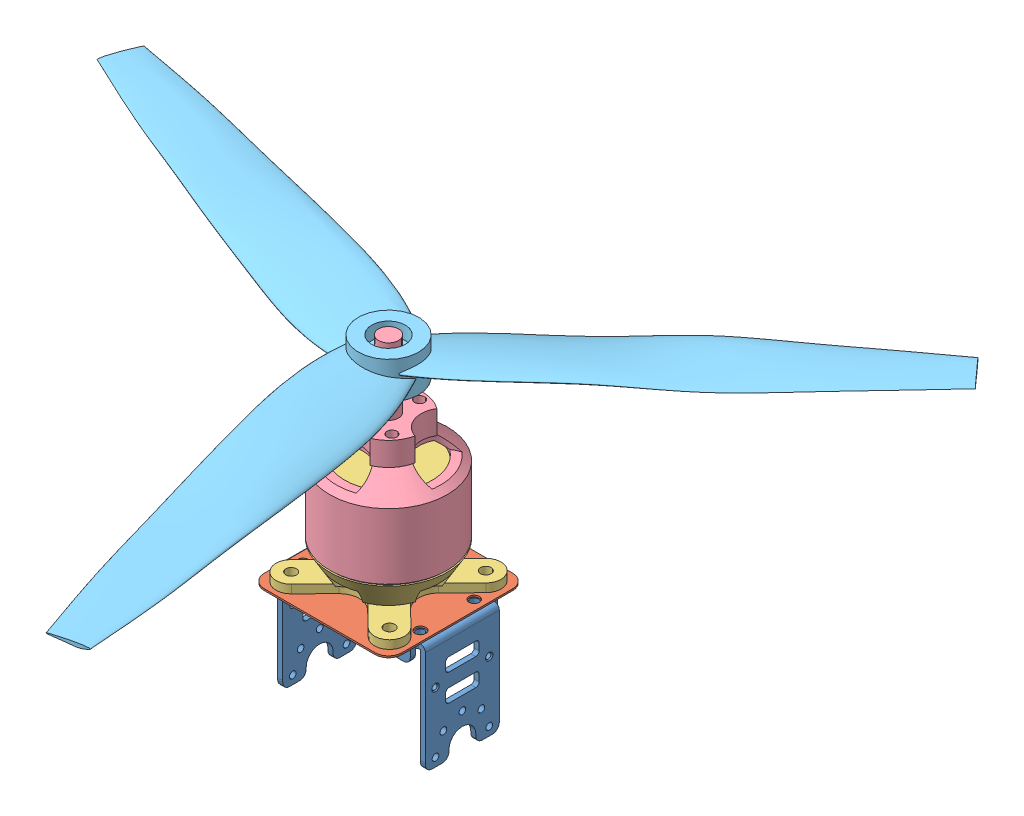
SolidWorks assembly montagem_superior, configuration Valor predeterminado. Lengths in mm.
Overall size (289.36 96.5 291.52).
6 component instances, 5 part files, 6 mates.
Components (placement in the parent):
- motor_suporte_rotativo-2: motor_suporte_rotativo [Valor predeterminado] at origin size (44 32.5 26)
- motor_chapa-3: motor_chapa [Valor predeterminado] at (0 30 0) x (1 0 0) z (0 1 0) size (41 41 0.5)
- motor-2: motor [Valor predeterminado] at (0 33 0) x (-0.714787 0 -0.699342) z (-0.699342 0 0.714787) size (50 63.5 50)
  - AXI2814-20-base-1: AXI2814-20-base [Valor predeterminado] at origin size (50 31 50)
  - AXI2814-20-rotor^AXI2814-20-1: AXI2814-20-rotor^AXI2814-20 [Valor predeterminado] x (0.079432 0 -0.99684) z (0.99684 0 0.079432) size (35 52.5 35)
- helice-2: helice [Valor predeterminado] at (0 88.5 0) x (0.669438 0 0.742868) z (0 1 0) size (220.39 190.91 11)
Mates (geometry in assembly coordinates):
- Concêntrico2: concentric anti-aligned: circle of motor_suporte_rotativo-2; circle of motor_chapa-3
- Coincidente1: coincident anti-aligned: plane of motor_suporte_rotativo-2 through (-20.5 30 11) normal (0 1 0); plane of motor_chapa-3 through (-16.5 30 16.5) normal (0 -1 0)
- Concêntrico3: concentric aligned: circle of motor_chapa-3; circle of motor-2/AXI2814-20-base-1
- Coincidente2: coincident anti-aligned: plane of motor_chapa-3 through (-16.5 30.5 16.5) normal (0 1 0); plane of motor-2/AXI2814-20-base-1 through (35.7775 30.5 -0.3908) normal (0 -1 0)
- Concêntrico4: concentric anti-aligned: circle of motor-2/AXI2814-20-rotor^AXI2814-20-1; circle of helice-2
- Coincidente4: coincident aligned: plane of motor-2/AXI2814-20-rotor^AXI2814-20-1 through (-4.276 94 0.3878) normal (0 1 0); plane of helice-2 through (0 94 0) normal (0 1 0)
